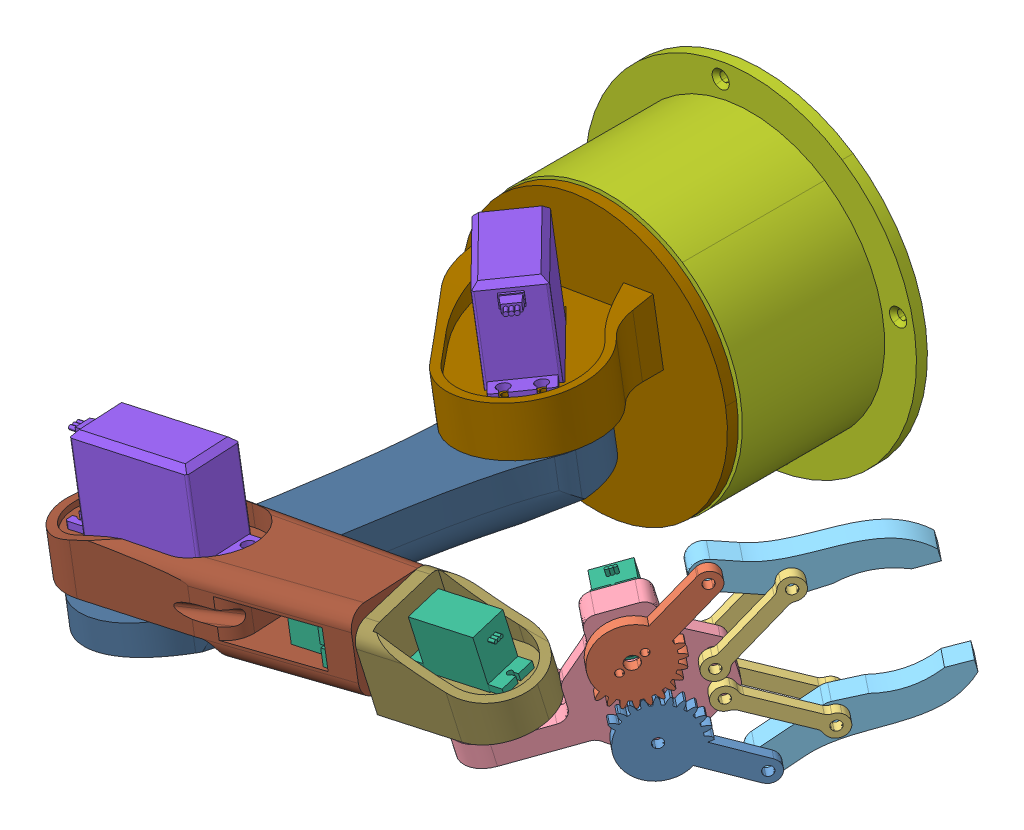
SolidWorks assembly Robotic Arm 3D Model, configuration Default. Lengths in mm.
Overall size (293.46 186.28 240.08).
22 component instances, 12 part files, 0 mates.
Components (placement in the parent):
- Robotic Arm 3D Model.STEP-1: Robotic Arm 3D Model.STEP [Default] at origin size (293.46 186.28 240.08)
  - Gripper Assembly.STEP-1: Gripper Assembly.STEP [Default] at (141.3527 -74.5202 258.0743) x (-0.152394 0.968393 0.197462) z (0.605548 0.249391 -0.755722) size (106.24 36.05 141.02)
    - gear1.STEP-1: gear1.STEP [Default] at (-22.9056 12.6028 63.2843) x (-0.581668 0 0.813426) z (-0.813426 0 -0.581668) size (49.29 4 26.63)
    - gear2.STEP-1: gear2.STEP [Default] at (5.149 12.6028 46.1292) x (-0.467421 0 -0.884035) z (0.884035 0 -0.467421) size (49.02 4 26.63)
    - grip link 1.STEP-1: grip link 1.STEP [Default] at (-26.7426 0.1028 100.5029) x (0.571471 0 -0.820623) z (0.820623 0 0.571471) size (39 4 8)
    - Gripper base.STEP-1: Gripper base.STEP [Default] at (-22.027 4.1028 80.0636) size (44.4 28 77)
    - grip link 1.STEP-2: grip link 1.STEP [Default] at (18.9346 0.1028 100.3298) x (-0.579406 0 -0.815039) z (0.815039 0 -0.579406) size (39 4 8)
    - Gripper 1.STEP-1: Gripper 1.STEP [Default] at (25.0683 4.1028 73.5645) x (0 1 0) z (0.39713 0 -0.917762) size (8.5 26.56 65.31)
    - Gripper 1.STEP-2: Gripper 1.STEP [Default] at (-32.1279 12.6028 73.5771) x (0 -1 0) z (-0.371396 0 -0.928475) size (8.5 26.56 65.31)
    - Servo Motor Micro  9g.STEP-1: Servo Motor Micro  9g.STEP [Default] at (4.773 -19.4472 55.0636) x (-1 0 0) z (0 0 -1) size (32.6 29.9 12.4)
    - grip link 1.STEP-3: grip link 1.STEP [Default] at (18.9346 12.6028 100.3298) x (-0.579406 0 -0.815039) z (0.815039 0 -0.579406) size (39 4 8)
    - grip link 1.STEP-4: grip link 1.STEP [Default] at (-26.7426 16.6028 100.5029) x (0.571471 0 -0.820623) z (-0.820623 0 -0.571471) size (39 4 8)
  - Base.STEP-1: Base.STEP [Default] at (40.7793 -92.8796 36.1076) x (-0.833886 0.551937 0) z (0.551937 0.833886 0) size (121.25 56 121.25)
  - Servo Motor MG996R.STEP-1: Servo Motor MG996R.STEP [Default] at (49.3266 -98.5369 45.3076) x (0.833886 -0.551937 0) z (-0.551937 -0.833886 0) size (55.8 47.4 21)
  - Waist.STEP-1: Waist.STEP [Default] at (40.7793 -92.8796 93.1076) x (0.167932 -0.985799 0) z (-0.985799 -0.167932 0) size (97 64.78 97)
  - Servo Motor MG996R.STEP-2: Servo Motor MG996R.STEP [Default] at (38.9186 -43.2877 126.313) x (-0.697065 -0.118746 -0.707107) z (-0.697065 -0.118746 0.707107) size (55.8 47.4 21)
  - Arm 01.STEP-1: Arm 01.STEP [Default] at (54.0236 -88.7974 133.5608) x (0.966472 0.16464 0.197041) z (0.167932 -0.985799 0) size (44.55 166.68 21.01)
  - Servo Motor Micro  9g.STEP-1: Servo Motor Micro  9g.STEP [Default] at (89.6249 -71.8786 247.3929) x (0.061757 0.01052 0.998036) z (-0.167932 0.985799 0) size (32.6 29.9 12.4)
  - Servo Motor MG996R.STEP-3: Servo Motor MG996R.STEP [Default] at (32.839 -44.3234 250.5661) x (0.983862 0.167602 -0.062647) z (-0.061757 -0.01052 -0.998036) size (55.8 47.4 21)
  - Arm 02 v3.STEP-1: Arm 02 v3.STEP [Default] at (64.0458 -81.8152 249.2808) x (0.061757 0.01052 0.998036) z (-0.167932 0.985799 0) size (38.01 115 27.01)
  - Arm 03.STEP-1: Arm 03.STEP [Default] at (119.1963 -67.8445 245.3213) x (0.093762 -0.184728 0.978307) z (-0.152394 0.968393 0.197462) size (33.01 46.01 28)
  - Servo Motor Micro  9g.STEP-2: Servo Motor Micro  9g.STEP [Default] at (139.5094 -49.9163 246.7597) x (-0.983862 -0.167602 0.062647) z (0.093762 -0.184728 0.978307) size (32.6 29.9 12.4)
